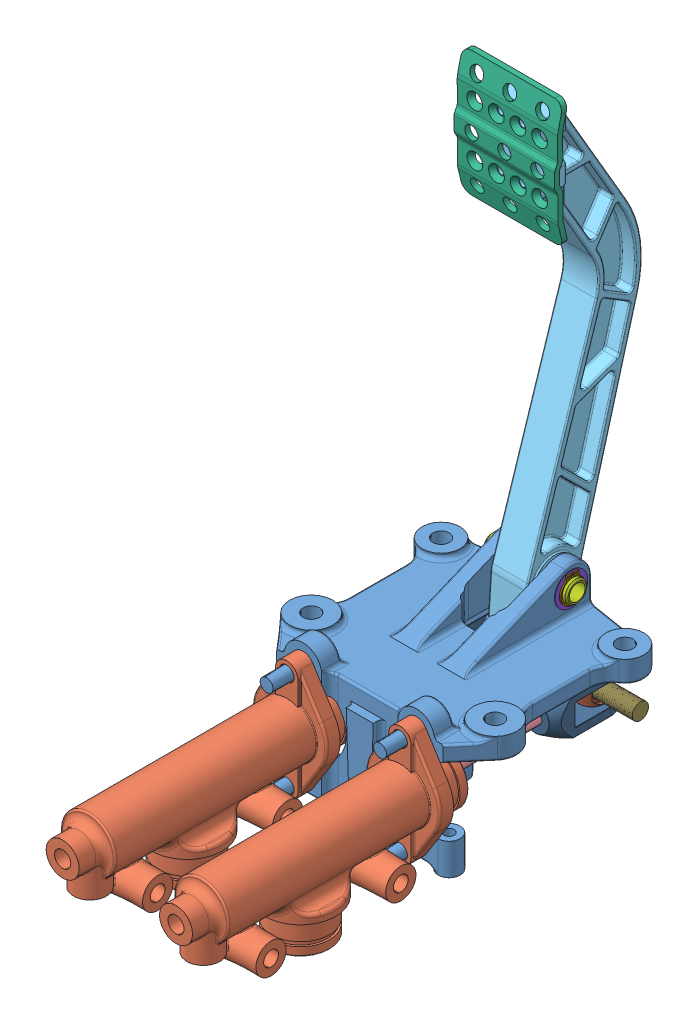
SolidWorks assembly BrakesAssem2, configuration Default. Lengths in mm.
Overall size (133.35 340.72 297.58).
22 component instances, 12 part files, 29 mates.
Components (placement in the parent):
- newBrakeMS_assem-1: newBrakeMS_assem [Default] at (94.891 166.2323 176.071) size (133.35 95.19 257.05)
  - pedalmount-1: pedalmount [Default] at (-8.0254 86.5254 126.5371) size (133.35 93.62 137.28)
  - mastercylinder asm-1: mastercylinder asm [Default] at (25.2486 67.4754 134.5381) x (1 0 0) z (0 0 -1) size (45.21 75.99 223.71)
    - mastercylinder-1: mastercylinder [Default] at origin size (45.21 75.99 154.88)
    - mastercylinder retaining washer-1: mastercylinder retaining washer [Default] at (0 0 17.145) size (20.83 20.83 1.91)
    - mastercylinder pushrod-1: mastercylinder pushrod [Default] at (0 0 90.551) x (-0.12806 0.991766 0) z (0 0 1) size (10.67 10.67 107.24)
  - mastercylinder asm-2: mastercylinder asm [Default] at (91.7966 67.4754 134.5381) x (1 0 0) z (0 0 -1) size (45.21 75.99 223.71)
    - mastercylinder-1: mastercylinder [Default] at origin size (45.21 75.99 154.88)
    - mastercylinder retaining washer-1: mastercylinder retaining washer [Default] at (0 0 17.145) size (20.83 20.83 1.91)
    - mastercylinder pushrod-1: mastercylinder pushrod [Default] at (0 0 90.551) x (-0.12806 0.991766 0) z (0 0 1) size (10.67 10.67 107.24)
- brake_pedal-1: brake_pedal [Default] at (152.8421 275.6176 198.9761) x (-1 0 0) z (0 -0.003692 0.999993) size (37.97 301.81 72.18)
- brake_pedal_pad-1: brake_pedal_pad [Default] at (182.5601 496.5881 214.4052) x (0 -0.999993 -0.003692) z (-1 0 0) size (73.98 8.25 58.98)
- bushing-1: bushing [Default] at (152.6707 275.6176 198.9761) x (0 0.840128 -0.542388) z (1 0 0) size (12.65 12.65 49.7)
- bushing washer-1: bushing washer [Default] at (174.0892 275.6176 198.9761) x (0 1 0) z (0 0 1) size (19.1 0.36 19.1)
- bushing washer-3: bushing washer [Default] at (133.3476 275.6176 198.9761) x (0 1 0) z (0 0 1) size (19.1 0.36 19.1)
- retainingring-1: retainingring [Default] at (174.0892 275.6176 198.9761) x (0 0 -1) z (1 0 0) size (14.22 15.93 0.89)
- retainingring-2: retainingring [Default] at (132.992 275.6176 198.9761) x (0 0 1) z (-1 0 0) size (14.22 15.93 0.89)
- clevis2022-1: clevis2022 [Default] at (120.3301 222.5316 199.4968) x (-1 0 0) z (0 0 -1) size (21.97 22.28 44.25)
- clevis2022-2: clevis2022 [Default] at (186.4971 244.8836 199.4968) x (1 0 0) z (0 0 -1) size (21.97 22.28 44.25)
- clevis pin2022-1: clevis pin2022 [Default] at (120.3301 221.8966 199.4968) x (0 0 1) z (-1 0 0) size (14.27 23.6 14.27)
- Balance bar2022-1: Balance bar2022 [Default] at (155.1762 233.9997 199.256) x (0 0.874504 0.485018) z (0 -0.485018 0.874504) size (20.15 121.21 20.15)
- clevis pin2022-2: clevis pin2022 [Default] at (186.4971 221.9728 199.4968) x (0 0 -1) z (1 0 0) size (14.27 23.6 14.27)
Mates (geometry in assembly coordinates):
- Concentric1: concentric aligned: cylinder of newBrakeMS_assem-1/pedalmount-1 through (115.3871 275.6176 198.9761) axis (1 0 0) radius 6.35; cylinder of brake_pedal-1 through (142.2376 275.6176 198.9761) axis (1 0 0) radius 6.35
- Coincident1: coincident anti-aligned: plane of newBrakeMS_assem-1/pedalmount-1 through (141.4756 262.2826 186.7841) normal (1 0 0); plane of brake_pedal-1 through (141.4756 275.6176 198.9761) normal (-1 0 0)
- Concentric2: concentric anti-aligned: cylinder of brake_pedal-1 through (159.1921 481.4021 199.7485) axis (0 -0.003692 0.999993) radius 2.0955; cone of brake_pedal_pad-1 through (159.1921 481.3443 215.3948) axis (0 0.003692 -0.999993)
- Concentric3: concentric anti-aligned: cylinder of brake_pedal-1 through (146.4921 511.8819 199.861) axis (0 -0.003692 0.999993) radius 2.0955; cone of brake_pedal_pad-1 through (146.4921 511.8241 215.5073) axis (0 0.003692 -0.999993)
- Coincident4: coincident anti-aligned: plane of brake_pedal-1 through (142.2376 516.534 212.5783) normal (0 -0.003692 0.999993); plane of brake_pedal_pad-1 through (123.5813 488.4343 212.4745) normal (0 0.003692 -0.999993)
- Coincident5: coincident anti-aligned: plane of newBrakeMS_assem-1/pedalmount-1 through (173.7336 400.5999 186.7841) normal (1 0 0); plane of bushing washer-1 through (173.7336 275.6176 198.9761) normal (-1 0 0)
- Concentric5: concentric aligned: cylinder of newBrakeMS_assem-1/pedalmount-1 through (115.3871 275.6176 198.9761) axis (1 0 0) radius 6.35; cylinder of bushing washer-1 through (173.7336 275.6176 198.9761) axis (1 0 0) radius 6.5659
- Coincident6: coincident anti-aligned: plane of newBrakeMS_assem-1/pedalmount-1 through (133.3476 400.5999 262.9841) normal (-1 0 0); plane of bushing washer-3 through (133.3476 275.6176 198.9761) normal (1 0 0)
- Concentric6: concentric aligned: cylinder of newBrakeMS_assem-1/pedalmount-1 through (115.3871 275.6176 198.9761) axis (1 0 0) radius 6.35; cylinder of bushing washer-3 through (132.992 275.6176 198.9761) axis (1 0 0) radius 6.5659
- Concentric8: concentric anti-aligned: cylinder of brake_pedal-1 through (142.2376 275.6176 198.9761) axis (1 0 0) radius 6.35; cylinder of bushing-1 through (177.5182 275.6176 198.9761) axis (-1 0 0) radius 6.3246
- Coincident9: coincident anti-aligned: plane of bushing washer-1 through (174.0892 275.6176 198.9761) normal (1 0 0); plane of retainingring-1 through (174.0892 282.4855 192.7505) normal (-1 0 0)
- Concentric9: concentric anti-aligned: cylinder of newBrakeMS_assem-1/pedalmount-1 through (115.3871 275.6176 198.9761) axis (1 0 0) radius 6.35; cylinder of retainingring-1 through (174.9782 275.6176 198.9761) axis (-1 0 0) radius 5.842
- Coincident10: coincident anti-aligned: plane of bushing washer-3 through (132.992 275.6176 198.9761) normal (-1 0 0); plane of retainingring-2 through (132.992 282.4855 205.2017) normal (1 0 0)
- Concentric10: concentric aligned: cylinder of newBrakeMS_assem-1/pedalmount-1 through (115.3871 275.6176 198.9761) axis (1 0 0) radius 6.35; cylinder of retainingring-2 through (132.103 275.6176 198.9761) axis (1 0 0) radius 5.842
- Coincident11: coincident anti-aligned: plane of bushing-1 through (174.9782 280.9311 195.5457) normal (-1 0 0); plane of retainingring-1 through (174.9782 282.4855 192.7505) normal (1 0 0)
- Concentric12: concentric anti-aligned: cylinder of newBrakeMS_assem-1/mastercylinder asm-1/mastercylinder pushrod-1 through (120.1396 233.7076 220.0581) axis (0 0 -1) radius 3.81; cylinder of clevis2022-1 through (120.1396 233.7076 232.7581) axis (0 0 1) radius 2.5527
- Coincident12: coincident aligned: plane of newBrakeMS_assem-1/mastercylinder asm-1/mastercylinder pushrod-1 through (120.1396 233.7076 220.0581) normal (0 0 -1); plane of clevis2022-1 through (133.0301 240.0195 220.0581) normal (0 0 -1)
- Concentric13: concentric anti-aligned: cylinder of newBrakeMS_assem-1/mastercylinder asm-2/mastercylinder pushrod-1 through (186.6876 233.7076 220.0581) axis (0 0 -1) radius 3.81; cylinder of clevis2022-2 through (186.6876 233.7076 232.7581) axis (0 0 1) radius 2.5527
- Coincident13: coincident aligned: plane of newBrakeMS_assem-1/mastercylinder asm-2/mastercylinder pushrod-1 through (186.6876 233.7076 220.0581) normal (0 0 -1); plane of clevis2022-2 through (173.7971 227.3957 220.0581) normal (0 0 -1)
- Parallel1: parallel aligned: plane of newBrakeMS_assem-1/pedalmount-1 through (220.2156 252.7576 255.2111) normal (0 -1 0); plane of clevis2022-2 through (186.4971 222.6078 199.4968) normal (0 -1 0)
- Parallel2: parallel aligned: plane of newBrakeMS_assem-1/pedalmount-1 through (220.2156 252.7576 255.2111) normal (0 -1 0); plane of clevis2022-1 through (120.3301 222.5316 199.4968) normal (0 -1 0)
- Concentric14: concentric aligned: circle of clevis2022-1; circle of clevis pin2022-1
- Concentric16: concentric anti-aligned: circle of clevis2022-2; circle of clevis pin2022-2
- Distance2: distance = 0.635 mm aligned: plane of clevis pin2022-1 through (120.3301 221.8966 199.4968) normal (0 -1 0); plane of clevis2022-1 through (120.3301 222.5316 199.4968) normal (0 -1 0)
- Parallel3: parallel aligned: plane of clevis2022-1 through (109.3446 244.8074 199.4968) normal (-1 0 0); plane of clevis pin2022-1 through (115.2501 233.6949 199.4968) normal (-1 0 0)
- Parallel4: parallel aligned: plane of clevis2022-2 through (197.4826 222.6078 199.4968) normal (1 0 0); plane of clevis pin2022-2 through (191.5771 233.7711 199.4968) normal (1 0 0)
- Distance3: distance = 0.635 mm aligned: plane of clevis pin2022-2 through (186.4971 221.9728 199.4968) normal (0 -1 0); plane of clevis2022-2 through (186.4971 222.6078 199.4968) normal (0 -1 0)
- Distance5: distance = 1.27 mm anti-aligned: plane of Balance bar2022-1 through (164.0662 228.6657 196.1764) normal (0 -1 0); plane of clevis2022-2 through (173.7971 227.3957 188.5113) normal (0 1 0)
- Distance7: distance = 15.24 mm: line of clevis2022-1 through (131.0616 240.0195 199.4968) axis (0 0 1); line of Balance bar2022-1 through (146.2862 239.3337 202.3356) axis (0 0 -1)
